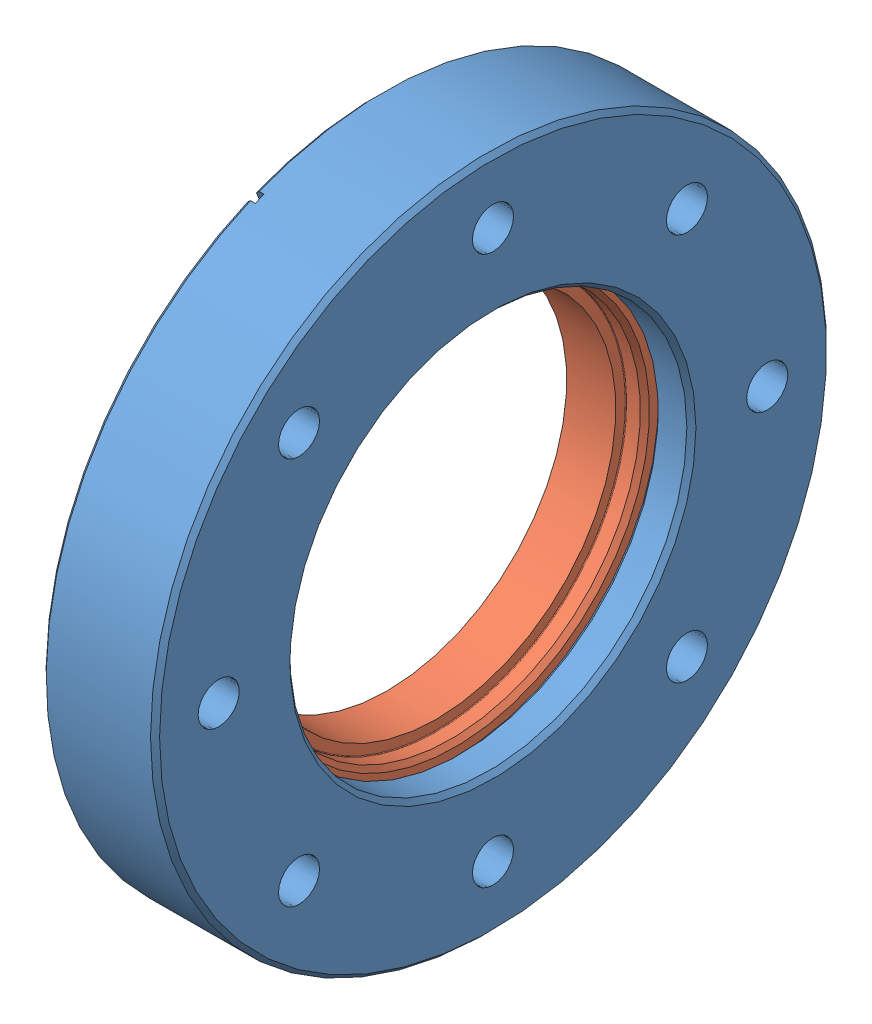
SolidWorks assembly 120021, configuration Default. Lengths in mm.
Overall size (19.06 113.54 113.54).
2 component instances, 2 part files, 2 mates.
Components (placement in the parent):
- 920004-1: 920004 [Default] at (16.7152 70.4618 88.0523) size (19.06 113.54 113.54)
- 910021-1: 910021 [Default] at (17.3756 70.4618 88.0523) x (1 0 0) z (0 0.068349 0.997661) size (11.99 82.32 82.32)
Mates (geometry in assembly coordinates):
- Concentric1: concentric aligned: cylinder of 920004-1 through (16.7152 70.4618 88.0523) axis (-1 0 0) radius 41.275; cylinder of 910021-1 through (17.3756 70.4618 88.0523) axis (-1 0 0) radius 41.1607
- Coincident1: coincident anti-aligned: plane of 920004-1 through (29.4152 111.7368 88.0523) normal (-1 0 0); plane of 910021-1 through (29.4152 102.2642 85.8735) normal (1 0 0)
